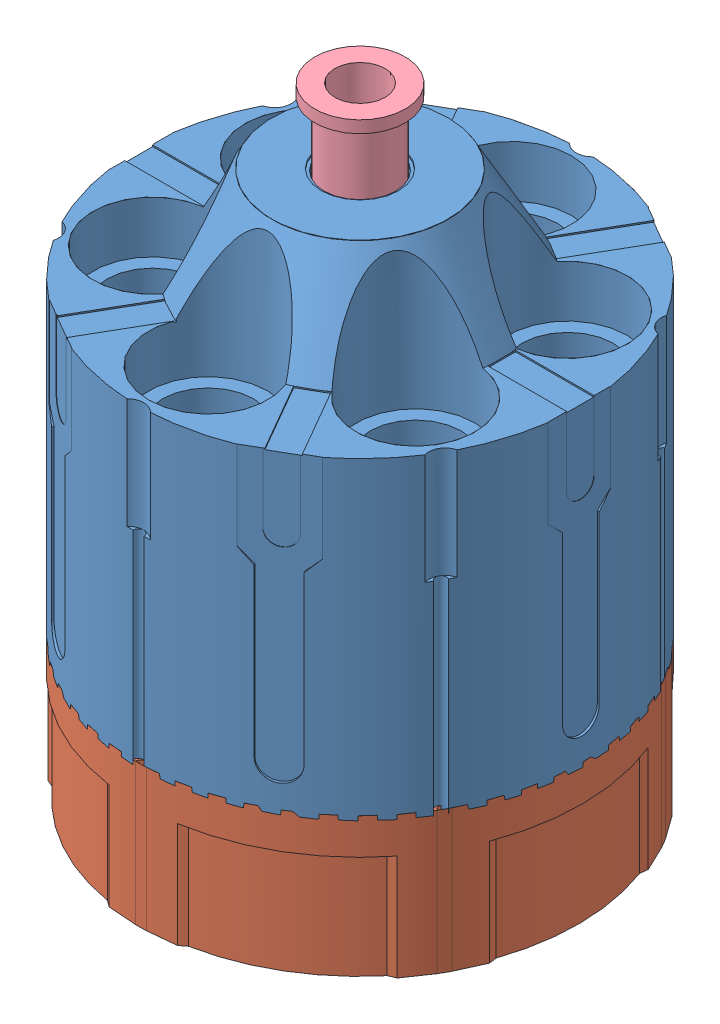
SolidWorks assembly CylinderAssembly, configuration Default. Lengths in mm.
Overall size (61.92 96.59 61.91).
4 component instances, 4 part files, 9 mates.
Components (placement in the parent):
- Cylinder_TopHalf-1: Cylinder_TopHalf [Default] at (10.3441 36.2557 54.3227) size (61.26 74 61.24)
- Cylinder_BottomHalf-1: Cylinder_BottomHalf [Default] at (10.3441 17.2957 54.3227) x (-0.999941 0 0.010888) z (-0.010888 0 -0.999941) size (61.26 49.19 61.25)
- Cylinder_BottomLock-1: Cylinder_BottomLock [Default] at (10.3441 6.3257 54.3227) x (0.135612 0 0.990762) z (-0.990762 0 0.135612) size (32 44 30.63)
- Cylinder_TopLock-1: Cylinder_TopLock [Default] at (10.3441 102.9157 54.3227) x (0.024849 0 0.999691) z (0.999691 0 -0.024849) size (12.51 52.56 12.51)
Mates (geometry in assembly coordinates):
- Concentric1: concentric: cylinder of Cylinder_TopHalf-1 through (10.3441 56.6757 54.3227) axis (0 -1 0) radius 3.15; cylinder of Cylinder_BottomHalf-1 through (10.3441 17.2957 54.3227) axis (0 1 0) radius 4.38
- Coincident3: coincident: plane of Cylinder_TopHalf-1 through (10.3441 18.6857 75.3175) normal (0 -1 0); plane of Cylinder_BottomHalf-1 through (10.3441 18.6857 54.3227) normal (0 1 0)
- Lock2: lock: unknown of Cylinder_TopHalf-1; unknown of Cylinder_BottomHalf-1
- Concentric5: concentric: cylinder of Cylinder_BottomHalf-1 through (10.3441 49.6657 54.3227) axis (0 -1 0) radius 7.275; cylinder of Cylinder_BottomLock-1 through (10.3441 50.3257 54.3227) axis (0 -1 0) radius 7.025
- Coincident4: coincident: plane of Cylinder_BottomHalf-1 through (10.3441 17.2957 54.3227) normal (0 -1 0); plane of Cylinder_BottomLock-1 through (10.3441 17.2957 54.3227) normal (0 1 0)
- Lock3: lock: unknown of Cylinder_BottomHalf-1; unknown of Cylinder_BottomLock-1
- Concentric8: concentric: cylinder of Cylinder_TopHalf-1 through (10.3441 57.2857 54.3227) axis (0 1 0) radius 4.945; cylinder of Cylinder_TopLock-1 through (10.3441 58.5057 54.3227) axis (0 1 0) radius 4.755
- Coincident5: coincident: plane of Cylinder_TopHalf-1 through (10.3441 91.7857 54.3227) normal (0 1 0); plane of Cylinder_TopLock-1 through (10.3441 91.7857 54.3227) normal (0 -1 0)
- Lock4: lock: unknown of Cylinder_TopHalf-1; unknown of Cylinder_TopLock-1
